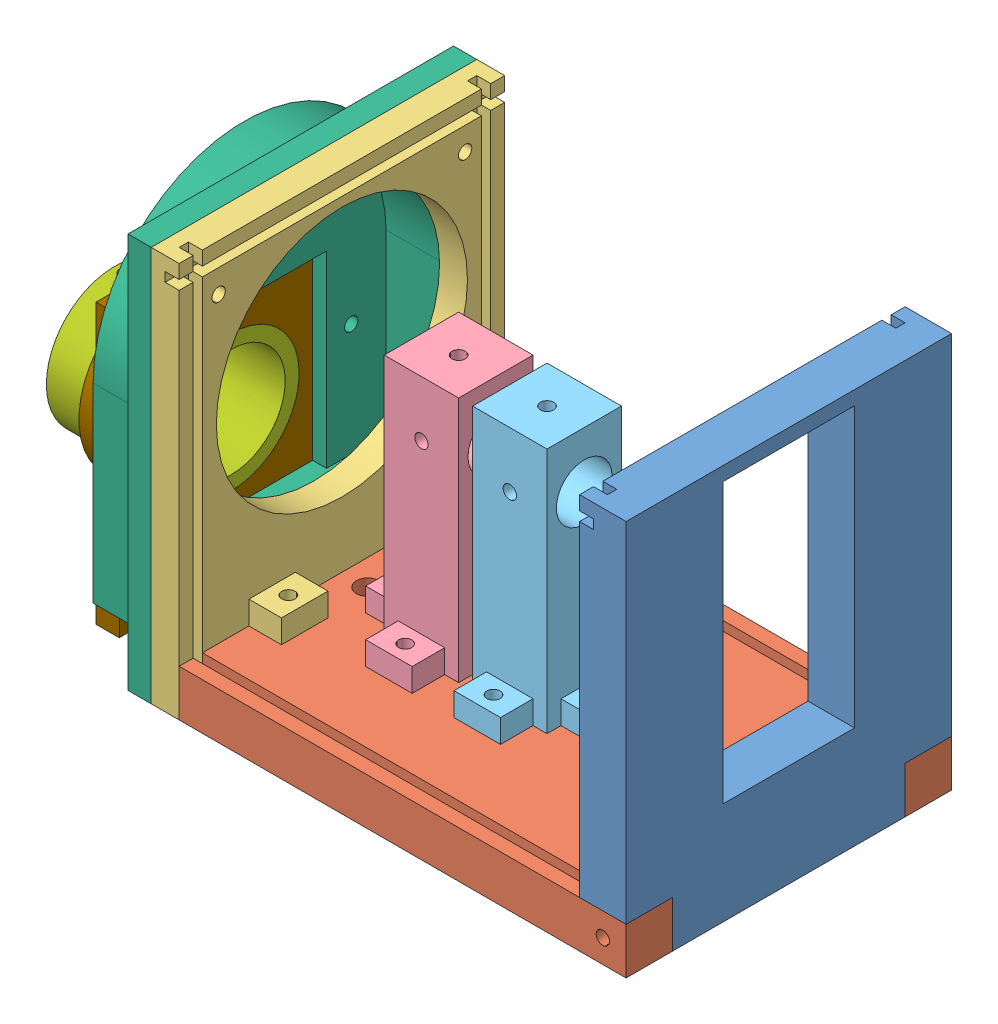
SolidWorks assembly Ensamblaje1, configuration Predeterminado. Lengths in mm.
Overall size (142.1 85 70).
9 component instances, 9 part files, 22 mates.
Components (placement in the parent):
- Pieza_manu01_1-1: Pieza_manu01_1 [Predeterminado] at (-49.6416 -35.0638 85) size (17 85 70)
- Pieza_manu01_2-1: Pieza_manu01_2 [Predeterminado] at (-106.1416 -35.0638 85) size (96.1 10 70)
- Pieza_manu01_3-1: Pieza_manu01_3 [Predeterminado] at (-143.7416 -35.0638 85) size (13 85 70)
- Pieza_manu01_4_1-1: Pieza_manu01_4_1 [Predeterminado] at (-115.6416 -28.0638 85) x (0 0 1) z (-1 0 0) size (30 56 23)
- Pieza_manu01_4_2-1: Pieza_manu01_4_2 [Predeterminado] at (-96.6416 -28.0638 85) x (0 0 -1) z (1 0 0) size (30 56 23)
- Pieza_manu02-1: Pieza_manu02 [Predeterminado] at (-151.7416 7.4362 85) x (0 -1 0) z (0 0 1) size (85 15 70)
- Pieza_manu03-1: Pieza_manu03 [Predeterminado] at (-161.7416 -4.3277 87.87) size (25 29.35 29.35)
- Pieza_manu04-1: Pieza_manu04 [Predeterminado] at (-174.7416 -4.3277 87.87) size (4 25.35 25.35)
- Pieza_manu05-1: Pieza_manu05 [Predeterminado] at (-161.7416 -4.3277 87.87) x (0 1 0) z (0 0 1) size (60 15 48)
Mates (geometry in assembly coordinates):
- Coincidente1: coincident anti-aligned: plane of Pieza_manu01_2-1 through (-106.1416 -28.0638 85) normal (0 1 0); plane of Pieza_manu01_4_1-1 through (-115.6416 -28.0638 85) normal (0 -1 0)
- Concéntrica2: concentric aligned: cylinder of Pieza_manu01_2-1 through (-127.1416 -35.0648 85) axis (0 1 0) radius 1.435; cylinder of Pieza_manu01_4_1-1 through (-127.1416 -28.0648 85) axis (0 1 0) radius 1.435
- Concéntrica3: concentric aligned: cylinder of Pieza_manu01_2-1 through (-115.6416 -35.0648 96.5) axis (0 1 0) radius 1.435; cylinder of Pieza_manu01_4_1-1 through (-115.6416 -28.0648 96.5) axis (0 1 0) radius 1.435
- Coincidente2: coincident anti-aligned: plane of Pieza_manu01_2-1 through (-106.1416 -28.0638 85) normal (0 1 0); plane of Pieza_manu01_4_2-1 through (-96.6416 -28.0638 85) normal (0 -1 0)
- Concéntrica5: concentric aligned: cylinder of Pieza_manu01_2-1 through (-85.1416 -35.0648 85) axis (0 1 0) radius 1.435; cylinder of Pieza_manu01_4_2-1 through (-85.1416 -28.0648 85) axis (0 1 0) radius 1.435
- Concéntrica6: concentric aligned: cylinder of Pieza_manu01_2-1 through (-96.6416 -35.0648 96.5) axis (0 1 0) radius 1.435; cylinder of Pieza_manu01_4_2-1 through (-96.6416 -28.0648 96.5) axis (0 1 0) radius 1.435
- Coincidente4: coincident anti-aligned: plane of Pieza_manu01_1-1 through (-54.6416 -25.0638 50) normal (-1 0 0); plane of Pieza_manu01_2-1 through (-54.6416 -25.0638 120) normal (1 0 0)
- Coincidente5: coincident anti-aligned: plane of Pieza_manu01_1-1 through (-44.6406 -35.0638 110) normal (0 0 1); plane of Pieza_manu01_2-1 through (-44.6416 -25.0638 110) normal (0 0 -1)
- Concéntrica8: concentric aligned: cylinder of Pieza_manu01_1-1 through (-49.6416 -30.0638 100) axis (0 0 1) radius 1.435; cylinder of Pieza_manu01_2-1 through (-49.6416 -30.0638 49.999) axis (0 0 1) radius 1.435
- Coincidente7: coincident: plane of Pieza_manu01_2-1 through (-140.7416 -25.0638 120) normal (-1 0 0); plane of Pieza_manu01_3-1 through (-140.7416 -25.0638 50) normal (1 0 0)
- Concéntrica9: concentric: cylinder of Pieza_manu01_2-1 through (-137.2416 -35.0648 100) axis (0 1 0) radius 1.435; cylinder of Pieza_manu01_3-1 through (-137.2416 -35.0648 100) axis (0 1 0) radius 1.435
- Coincidente8: coincident anti-aligned: plane of Pieza_manu01_2-1 through (-106.1416 -25.0638 85) normal (0 1 0); plane of Pieza_manu01_3-1 through (-133.7416 -25.0638 105) normal (0 -1 0)
- Coincidente9: coincident: plane of Pieza_manu01_3-1 through (-146.7416 -25.0638 50) normal (-1 0 0); plane of Pieza_manu02-1 through (-146.7416 7.4362 85) normal (1 0 0)
- Concéntrica10: concentric: cylinder of Pieza_manu01_3-1 through (-131.7416 39.9362 111.5) axis (-1 0 0) radius 1.435; cylinder of Pieza_manu02-1 through (-146.7416 39.9362 111.5) axis (-1 0 0) radius 1.435
- Concéntrica11: concentric aligned: cylinder of Pieza_manu01_3-1 through (-131.7416 -30.0638 111.5) axis (-1 0 0) radius 1.435; cylinder of Pieza_manu02-1 through (-146.7416 -30.0638 111.5) axis (-1 0 0) radius 1.435
- Coincidente10: coincident: plane of Pieza_manu02-1 through (-161.7416 15.9362 85) normal (-1 0 0); plane of Pieza_manu05-1 through (-161.7416 -4.3277 87.87) normal (1 0 0)
- Tangente1: tangent: cylinder of Pieza_manu02-1 through (-146.7416 2.1562 65) axis (-1 0 0) radius 1.435; plane of Pieza_manu05-1 through (-161.7416 -19.3277 66.435) normal (0 0 1)
- Tangente2: tangent aligned: cylinder of Pieza_manu02-1 through (-146.7416 2.1562 105) axis (-1 0 0) radius 1.435; plane of Pieza_manu05-1 through (-161.7416 -19.3277 106.435) normal (0 0 1)
- Concéntrica12: concentric: cylinder of Pieza_manu03-1 through (-192.109 -4.3277 87.87) axis (-1 0 0) radius 14.675; cylinder of Pieza_manu05-1 through (-176.7426 -4.3277 87.87) axis (1 0 0) radius 14.675
- Coincidente11: coincident aligned: plane of Pieza_manu03-1 through (-161.7416 -4.3277 73.195) normal (1 0 0); circle of Pieza_manu05-1
- Concéntrica13: concentric: cylinder of Pieza_manu03-1 through (-192.109 -4.3277 87.87) axis (-1 0 0) radius 12.675; cylinder of Pieza_manu04-1 through (-195.5267 -4.3277 87.87) axis (-1 0 0) radius 12.675
- Coincidente12: coincident anti-aligned: plane of Pieza_manu03-1 through (-174.7416 -4.3277 76.195) normal (-1 0 0); plane of Pieza_manu04-1 through (-174.7416 -4.3277 75.195) normal (1 0 0)
